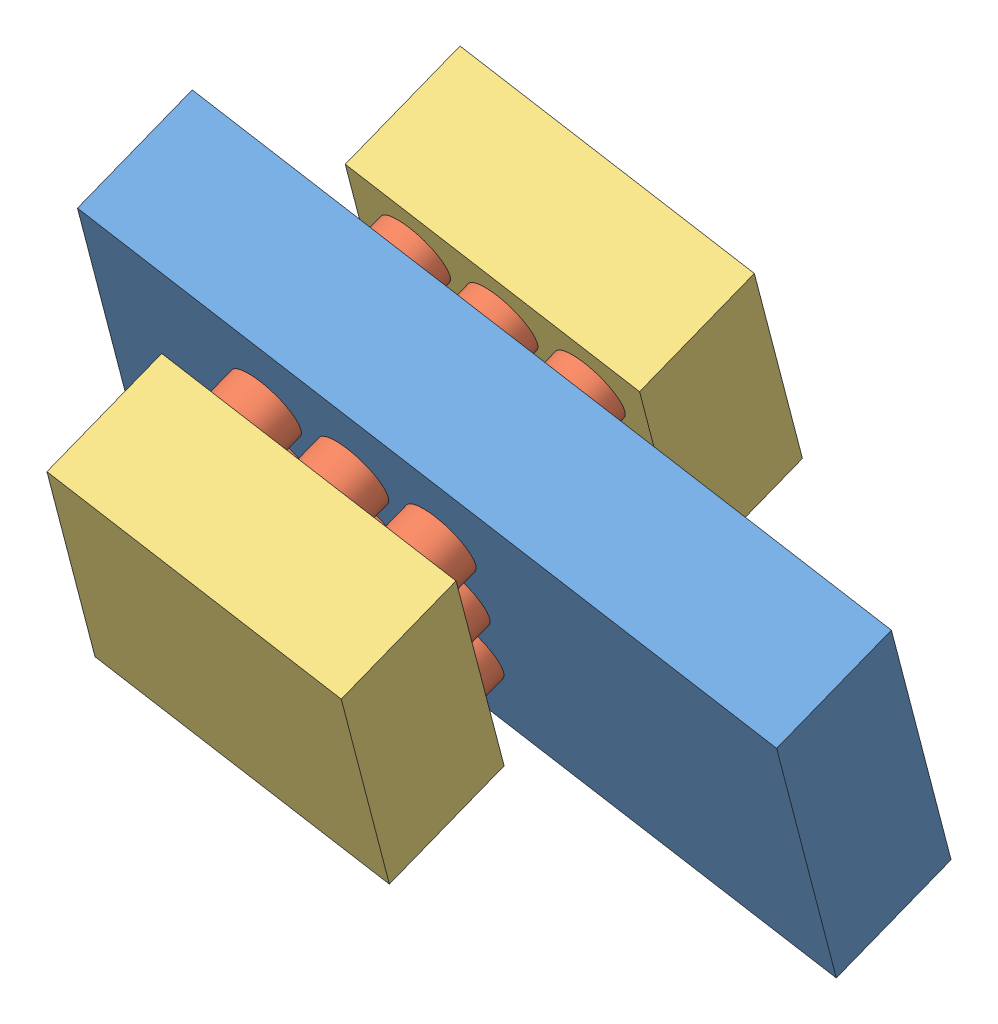
SolidWorks assembly 1119cylin, configuration Default. Lengths in mm.
Overall size (63.07 49.45 44.22).
5 component instances, 3 part files, 11 mates.
Components (placement in the parent):
- 插头-1: 插头 [默认] at (-12.2413 38.3913 43.633) x (-0.246276 -0.877721 -0.411041) z (0.968324 -0.240854 -0.065863) size (30 12.41 56)
- sensor cyli bump-2: sensor cyli bump [Default] at (16.7671 38.4949 25.1975) x (0.968324 -0.240854 -0.065863) z (-0.041191 -0.414241 0.909235) size (50 30 3)
- sensor cyli bump-3: sensor cyli bump [Default] at (16.2316 33.1098 37.0175) x (0.968324 -0.240854 -0.065863) z (-0.041191 -0.414241 0.909235) size (50 30 3)
- sensorbase-1: sensorbase [Default] at (16.5861 23.5657 57.9813) x (0.968324 -0.240854 -0.065863) z (0.041191 0.414241 -0.909235) size (23.58 24.17 10)
- sensorbase-2: sensorbase [Default] at (18.0482 38.4044 25.2143) x (0.968324 -0.240854 -0.065863) z (-0.041191 -0.414241 0.909235) size (23.58 24.17 10)
Mates (geometry in assembly coordinates):
- 重合2: coincident anti-aligned: plane of 插头-1 through (35.969 24.2774 44.886) normal (-0.041191 -0.414241 0.909235); plane of sensor cyli bump-3 through (-12.3175 19.1859 40.3788) normal (0.041191 0.414241 -0.909235)
- 重合3: coincident anti-aligned: plane of 插头-1 through (36.3809 28.4198 35.7936) normal (0.041191 0.414241 -0.909235); plane of sensor cyli bump-2 through (6.9252 42.2651 40.767) normal (-0.041191 -0.414241 0.909235)
- 同心1: concentric aligned: cylinder of sensor cyli bump-2 through (6.9252 42.2651 40.767) axis (0.041191 0.414241 -0.909235) radius 2.8; cylinder of sensor cyli bump-3 through (6.3897 36.88 52.5871) axis (0.041191 0.414241 -0.909235) radius 2.8
- 同心2: concentric aligned: cylinder of sensor cyli bump-2 through (3.4773 29.9771 35.0124) axis (0.041191 0.414241 -0.909235) radius 2.8; cylinder of sensor cyli bump-3 through (2.9418 24.5919 46.8325) axis (0.041191 0.414241 -0.909235) radius 2.8
- 平行2: parallel anti-aligned: line of 插头-1 through (-12.0353 40.4625 39.0868) axis (0.968324 -0.240854 -0.065863); line of sensor cyli bump-2 through (5.3248 37.3638 35.162) axis (-0.968324 0.240854 0.065863)
- 重合7: coincident anti-aligned: plane of sensor cyli bump-3 through (6.3897 36.88 52.5871) normal (-0.041191 -0.414241 0.909235); plane of sensorbase-1 through (16.998 27.7081 48.889) normal (0.041191 0.414241 -0.909235)
- 重合8: coincident anti-aligned: plane of sensor cyli bump-2 through (-11.782 24.5711 28.5587) normal (0.041191 0.414241 -0.909235); plane of sensorbase-2 through (17.6363 34.262 34.3066) normal (-0.041191 -0.414241 0.909235)
- 重合9: coincident anti-aligned: line of sensor cyli bump-2 through (5.3248 37.3638 35.162) axis (-0.968324 0.240854 0.065863); line of sensorbase-2 through (-6.0895 40.2029 35.9384) axis (0.968324 -0.240854 -0.065863)
- 重合10: coincident aligned: line of sensor cyli bump-2 through (5.3248 37.3638 35.162) axis (0.246276 0.877721 0.411041); line of sensorbase-2 through (2.348 26.7546 30.1937) axis (0.246276 0.877721 0.411041)
- 重合11: coincident aligned: plane of sensorbase-1 through (22.1353 69.4642 -14.0495) normal (0.246276 0.877721 0.411041); plane of sensorbase-2 through (-3.1127 50.8122 40.9068) normal (0.246276 0.877721 0.411041)
- 重合12: coincident aligned: plane of sensorbase-1 through (-9.7253 22.9659 45.5178) normal (-0.968324 0.240854 0.065863); plane of sensorbase-2 through (-3.1127 50.8122 40.9068) normal (-0.968324 0.240854 0.065863)
